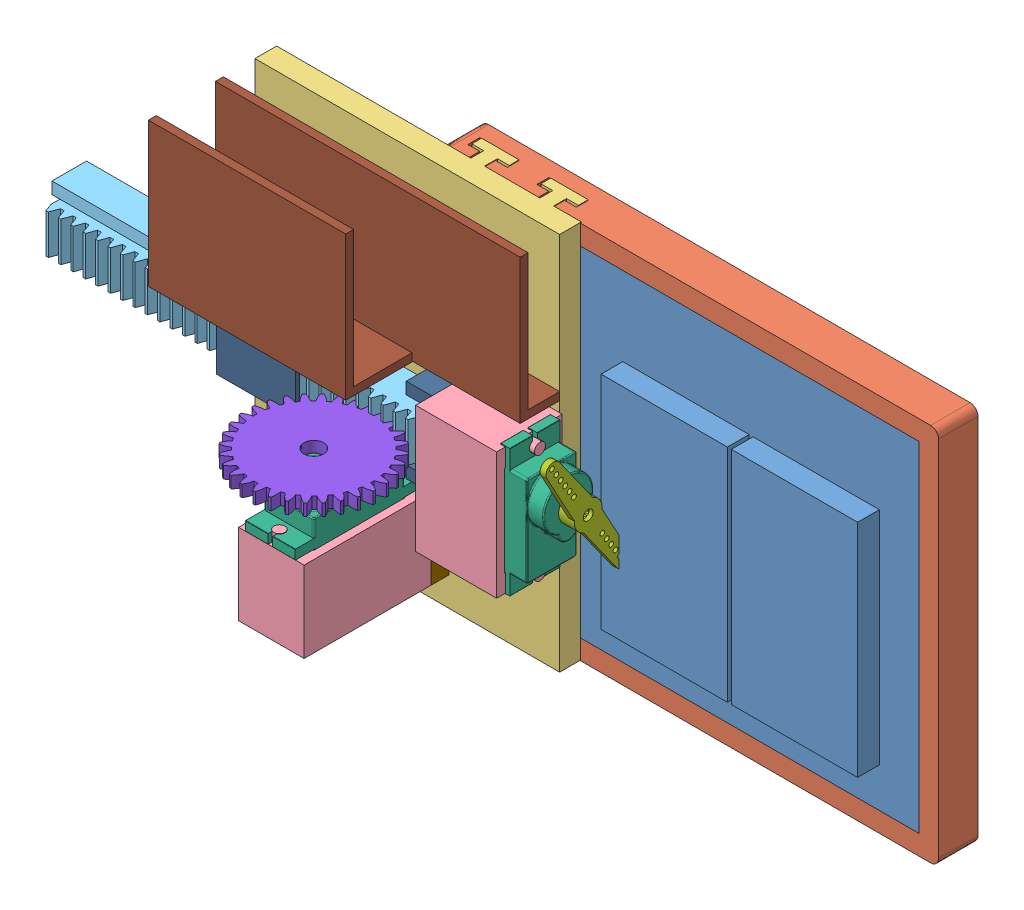
SolidWorks assembly 总装配体v2, configuration 默认. Lengths in mm.
Overall size (210.62 96.14 64.96).
13 component instances, 11 part files, 34 mates.
Components (placement in the parent):
- 开关建模-1: 开关建模 [默认] at origin size (86 86 15.5)
- 底座框架-1: 底座框架 [默认] at origin size (126 96 10)
- 活动底板-2: 活动底板 [默认] at (-39.7003 6.3474 -133.25) size (77.19 96.05 11.25)
- 舵机外壳v2-2: 舵机外壳v2 [默认] at (-59.1174 -7.0177 7.25) x (0 -1 0) z (0 0 1) size (32.1 23 16.6)
- 带槽齿条-1: 带槽齿条 [默认] at (-82.9155 8.9243 -166.694) size (100 15 11)
- SG90_Model_B.step-1: SG90_Model_B.step [默认] at (-59.1174 -6.9177 13.35) x (0 0 1) z (-1 0 0) size (12.61 32.4 29.2)
- SG90_Arm_04_Custom.step-1: SG90_Arm_04_Custom.step [默认] at (-27.4174 -1.7177 13.35) x (0 -0.529604 0.848245) z (-1 0 0) size (7 37 4)
- spur gear_gb-1: spur gear_gb [GB - Spur gear 1M 32T 20PA 3FW ---S32A75H50L5.0N] at (-79.2886 -4.1779 31) x (0 -1 0) z (-0.702378 0 0.711805) size (3 33.89 33.89)
- SG90_Model_B.step-2: SG90_Model_B.step [默认] at (-79.2886 -35.8779 25.8) x (1 0 0) z (0 -1 0) size (12.61 32.4 29.2)
- 舵机外壳v2-3: 舵机外壳v2 [默认] at (-85.3886 -37.0779 25.9) x (0 0 -1) z (1 0 0) size (32.1 23 16.6)
- 零件3^总装配体v2-1: 零件3^总装配体v2 [默认] at (-39.7003 6.3474 5.25) size (16.6 20.5 4.6) (virtual)
- 零件4^总装配体v2-1: 零件4^总装配体v2 [默认] at (-39.7003 6.3474 5.25) size (53.93 21.4 13.1) (virtual)
- 零件5^总装配体v2-1: 零件5^总装配体v2 [默认] at (-39.7003 6.3474 5.25) size (77.19 36.47 27) (virtual)
Mates (geometry in assembly coordinates):
- 重合1: coincident anti-aligned: plane of 开关建模-1 through (-43 43 -131.6224) normal (-1 0 0); plane of 底座框架-1 through (-43 43 -10) normal (1 0 0)
- 重合2: coincident anti-aligned: plane of 开关建模-1 through (-43 -43 -131.6224) normal (0 -1 0); plane of 底座框架-1 through (-43 -43 -10) normal (0 1 0)
- 重合3: coincident anti-aligned: plane of 底座框架-1 through (-74.2475 -54.6576 -6) normal (0 0 1); plane of 活动底板-2 through (-64.2525 -53.9563 -6) normal (0 0 -1)
- 重合4: coincident anti-aligned: plane of 底座框架-1 through (-46.7525 -54.6576 -3) normal (-1 0 0); plane of 活动底板-2 through (-46.7525 -53.9563 -3.5) normal (1 0 0)
- 重合6: coincident aligned: plane of 开关建模-1 through (0 0 0) normal (0 0 1); plane of 底座框架-1 through (0 0 0) normal (0 0 1)
- 重合7: coincident anti-aligned: plane of 舵机外壳v2-2 through (-62.6174 21.2732 19.45) normal (-1 0 0); plane of 带槽齿条-1 through (-62.6174 -10.6779 5.25) normal (1 0 0)
- 重合8: coincident anti-aligned: plane of 活动底板-2 through (0.25 0.144 5.25) normal (0 0 1); plane of 舵机外壳v2-2 through (-59.1174 -7.0177 5.25) normal (0 0 -1)
- 重合10: coincident anti-aligned: plane of 舵机外壳v2-2 through (-59.1174 4.5323 19.45) normal (1 0 0); plane of SG90_Model_B.step-1 through (-59.1174 -6.9177 13.35) normal (-1 0 0)
- 平行1: parallel anti-aligned: plane of 舵机外壳v2-2 through (-59.1174 -18.5677 19.45) normal (0 1 0); plane of SG90_Model_B.step-1 through (-59.1174 -18.4177 19.65) normal (0 -1 0)
- 距离1: distance = 1 mm anti-aligned: plane of SG90_Arm_04_Custom.step-1 through (-31.4174 -1.7177 13.35) normal (-1 0 0); plane of SG90_Model_B.step-1 through (-32.4174 -2.6677 13.35) normal (1 0 0)
- 同心8: concentric aligned: circle of SG90_Model_B.step-1; circle of SG90_Arm_04_Custom.step-1
- 同心12: concentric anti-aligned: circle of 舵机外壳v2-2; circle of SG90_Model_B.step-1
- 距离2: distance = 2.2102 mm aligned: plane of 带槽齿条-1 through (-62.6174 -0.6779 16.25) normal (0 1 0); plane of 舵机外壳v2-2 through (-42.1174 1.5323 15.75) normal (0 1 0)
- 宽度2: width anti-aligned: plane of GB - Spur gear 1M 32T 20PA 3FW ---S32A75H50L5.0N-1 through (-79.2886 -7.1779 31) normal (0 -1 0); plane of 带槽齿条-1 through (-79.2886 -4.1779 31) normal (0 1 0); plane of GB - Spur gear 1M 32T 20PA 3FW ---S32A75H50L5.0N-1 through (-62.6174 -0.6779 16.25) normal (0 1 0); plane of 带槽齿条-1 through (-62.6174 -10.6779 16.25) normal (0 -1 0)
- 相切1: tangent anti-aligned: plane of 带槽齿条-1 through (-81.9114 -10.6779 14) normal (0 0 1); cylinder of GB - Spur gear 1M 32T 20PA 3FW ---S32A75H50L5.0N-1 through (-79.2886 5.8221 31) axis (0 1 0) radius 17
- 重合19: coincident aligned: line of 舵机外壳v2-2 through (-62.6174 -23.0677 5.25) axis (0 1 0); line of 带槽齿条-1 through (-62.6174 -10.6779 5.25) axis (0 1 0)
- 同心13: concentric anti-aligned: circle of GB - Spur gear 1M 32T 20PA 3FW ---S32A75H50L5.0N-1; circle of SG90_Model_B.step-2
- 距离3: distance = 2 mm anti-aligned: plane of SG90_Model_B.step-2 through (-79.2886 -9.1779 30.05) normal (0 1 0); plane of spur gear_gb-1 through (-79.2886 -7.1779 31) normal (0 -1 0)
- 同心14: concentric anti-aligned: circle of SG90_Model_B.step-2; circle of 舵机外壳v2-3
- 平行4: parallel anti-aligned: plane of SG90_Model_B.step-2 through (-72.9886 -35.8779 37.3) normal (1 0 0); plane of 舵机外壳v2-3 through (-72.7886 -37.0779 25.9) normal (-1 0 0)
- 重合21: coincident anti-aligned: plane of SG90_Model_B.step-2 through (-79.2886 -20.0779 39.65) normal (0 -1 0); plane of 舵机外壳v2-3 through (-73.1886 -20.0779 37.45) normal (0 1 0)
- 平行5: parallel anti-aligned: plane of 活动底板-2 through (0.25 0.144 5.25) normal (0 0 1); plane of 舵机外壳v2-3 through (-73.1886 -41.5779 9.85) normal (0 0 -1)
- 在位1: in place: plane of 活动底板-2 through (0.25 0.144 5.25) normal (0 0 1); plane of ? through (0 0 5.25) normal (0 0 1); moOrthogonalPlaneRef_w of 活动底板-2 through (0.25 0.144 5.25) normal (0 0 1); plane of ? through (0 0 5.25) normal (0 1 0); plane of 活动底板-2 through (0.25 0.144 5.25) normal (0 0 1); plane of ? through (0 0 5.25) normal (1 0 0); plane of 活动底板-2 through (0.25 0.144 5.25) normal (0 0 1); unknown of ?
- 重合22: coincident aligned: plane of 活动底板-2; plane of 零件3^总装配体v2-1
- 重合23: coincident aligned: moOrthogonalPlaneRef_w of 活动底板-2 through (-39.7003 6.3474 5.25) normal (0 1 0); plane of 零件3^总装配体v2-1 through (-39.7003 6.3474 5.25) normal (0 1 0)
- 重合24: coincident anti-aligned: moOrthogonalPlaneRef_w of 活动底板-2 through (-39.7003 6.3474 5.25) normal (-1 0 0); plane of 零件3^总装配体v2-1 through (-39.7003 6.3474 5.25) normal (1 0 0)
- 在位2: in place: plane of 活动底板-2 through (0.25 0.144 5.25) normal (0 0 1); plane of ? through (0 0 5.25) normal (0 0 1); plane of 活动底板-2 through (0.25 0.144 5.25) normal (0 0 1); plane of ? through (0 0 5.25) normal (0 1 0); plane of 活动底板-2 through (0.25 0.144 5.25) normal (0 0 1); plane of ? through (0 0 5.25) normal (1 0 0); plane of 活动底板-2 through (0.25 0.144 5.25) normal (0 0 1); unknown of ?
- 重合25: coincident aligned: plane of 活动底板-2; plane of 零件4^总装配体v2-1
- 重合26: coincident aligned: moOrthogonalPlaneRef_w of 活动底板-2 through (-39.7003 6.3474 5.25) normal (0 1 0); plane of 零件4^总装配体v2-1 through (-39.7003 6.3474 5.25) normal (0 1 0)
- 重合27: coincident anti-aligned: moOrthogonalPlaneRef_w of 活动底板-2 through (-39.7003 6.3474 5.25) normal (-1 0 0); plane of 零件4^总装配体v2-1 through (-39.7003 6.3474 5.25) normal (1 0 0)
- 在位3: in place: plane of 活动底板-2 through (0.25 0.144 5.25) normal (0 0 1); plane of ? through (0 0 5.25) normal (0 0 1); plane of 活动底板-2 through (0.25 0.144 5.25) normal (0 0 1); plane of ? through (0 0 5.25) normal (0 1 0); plane of 活动底板-2 through (0.25 0.144 5.25) normal (0 0 1); plane of ? through (0 0 5.25) normal (1 0 0); plane of 活动底板-2 through (0.25 0.144 5.25) normal (0 0 1); unknown of ?
- 重合22: coincident aligned: plane of 活动底板-2; plane of 零件5^总装配体v2-1
- 重合23: coincident aligned: moOrthogonalPlaneRef_w of 活动底板-2 through (-39.7003 6.3474 5.25) normal (0 1 0); plane of 零件5^总装配体v2-1 through (-39.7003 6.3474 5.25) normal (0 1 0)
- 重合24: coincident anti-aligned: moOrthogonalPlaneRef_w of 活动底板-2 through (-39.7003 6.3474 5.25) normal (-1 0 0); plane of 零件5^总装配体v2-1 through (-39.7003 6.3474 5.25) normal (1 0 0)
